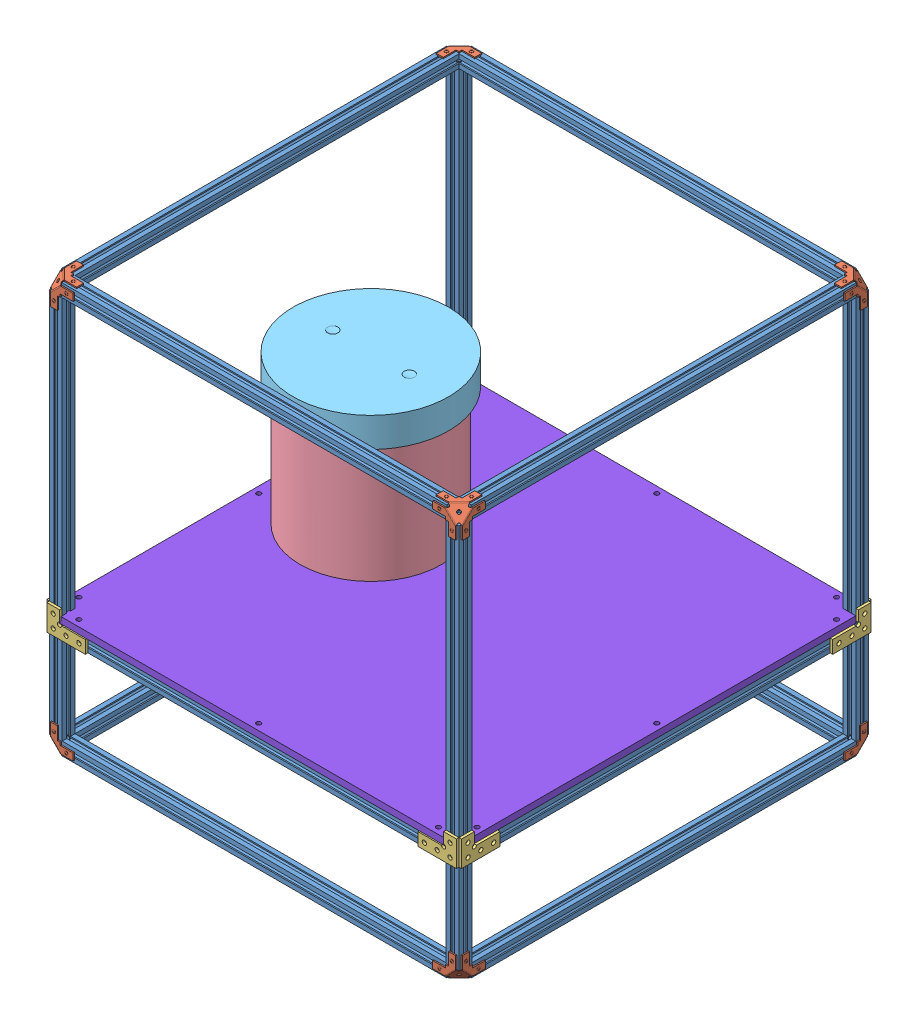
SolidWorks assembly body_assem, configuration Default. Lengths in mm.
Overall size (323 321.3 323).
38 component instances, 8 part files, 96 mates.
Components (placement in the parent):
- 1010extrusion_300-13: 1010extrusion_300 [Default] at (-139.7052 7.1905 -149.8431) size (10 10 300)
- 1959N550_MINIATURE T-SLOTTED FRAMING-9: 1959N550_MINIATURE T-SLOTTED FRAMING [1959N55] at (-145.2052 6.6905 155.1569) x (0 0 1) z (-1 0 0) size (20.65 20.65 20.65)
- 1010extrusion_300-14: 1010extrusion_300 [Default] at (164.7948 7.1905 154.6569) x (0 0 1) z (-1 0 0) size (10 10 300)
- 1010extrusion_300-15: 1010extrusion_300 [Default] at (-139.7052 311.6905 154.6569) x (1 0 0) z (0 -1 0) size (10 10 300)
- 1959N550_MINIATURE T-SLOTTED FRAMING-10: 1959N550_MINIATURE T-SLOTTED FRAMING [1959N55] at (-140.2052 6.6905 -159.8431) x (-1 0 0) z (0 0 -1) size (20.65 20.65 20.65)
- 1010extrusion_300-16: 1010extrusion_300 [Default] at (-139.7052 311.6905 -154.3431) x (1 0 0) z (0 -1 0) size (10 10 300)
- 1010extrusion_300-17: 1010extrusion_300 [Default] at (164.7948 7.1905 -154.3431) x (0 0 1) z (-1 0 0) size (10 10 300)
- 1959N550_MINIATURE T-SLOTTED FRAMING-11: 1959N550_MINIATURE T-SLOTTED FRAMING [1959N55] at (169.7948 6.6905 160.1569) size (20.65 20.65 20.65)
- 1959N550_MINIATURE T-SLOTTED FRAMING-12: 1959N550_MINIATURE T-SLOTTED FRAMING [1959N55] at (174.7948 6.6905 -154.8431) x (0 0 -1) z (1 0 0) size (20.65 20.65 20.65)
- 1010extrusion_300-18: 1010extrusion_300 [Default] at (169.2948 311.6905 154.6569) x (1 0 0) z (0 -1 0) size (10 10 300)
- 1010extrusion_300-19: 1010extrusion_300 [Default] at (169.2948 7.1905 -149.8431) size (10 10 300)
- 1010extrusion_300-20: 1010extrusion_300 [Default] at (169.2948 311.6905 -154.3431) x (1 0 0) z (0 -1 0) size (10 10 300)
- 1010extrusion_300-21: 1010extrusion_300 [Default] at (169.2948 316.1905 150.1569) x (1 0 0) z (0 0 -1) size (10 10 300)
- 1010extrusion_300-22: 1010extrusion_300 [Default] at (164.7948 316.1905 -154.3431) x (0 0 -1) z (-1 0 0) size (10 10 300)
- 1959N550_MINIATURE T-SLOTTED FRAMING-13: 1959N550_MINIATURE T-SLOTTED FRAMING [1959N55] at (169.7948 316.6905 -159.8431) x (1 0 0) z (0 0 -1) size (20.65 20.65 20.65)
- 1959N550_MINIATURE T-SLOTTED FRAMING-14: 1959N550_MINIATURE T-SLOTTED FRAMING [1959N55] at (174.7948 316.6905 155.1569) x (0 0 1) z (1 0 0) size (20.65 20.65 20.65)
- 1010extrusion_300-23: 1010extrusion_300 [Default] at (164.7948 316.1905 154.6569) x (0 0 -1) z (-1 0 0) size (10 10 300)
- 1959N550_MINIATURE T-SLOTTED FRAMING-15: 1959N550_MINIATURE T-SLOTTED FRAMING [1959N55] at (-140.2052 316.6905 160.1569) x (-1 0 0) z (0 0 1) size (20.65 20.65 20.65)
- 1010extrusion_300-24: 1010extrusion_300 [Default] at (-139.7052 316.1905 150.1569) x (1 0 0) z (0 0 -1) size (10 10 300)
- 1959N550_MINIATURE T-SLOTTED FRAMING-16: 1959N550_MINIATURE T-SLOTTED FRAMING [1959N55] at (-145.2052 316.6905 -154.8431) x (0 0 -1) z (-1 0 0) size (20.65 20.65 20.65)
- 1010extrusion_300-25: 1010extrusion_300 [Default] at (169.2948 86.6905 -150.3431) size (10 10 300)
- 1010extrusion_300-26: 1010extrusion_300 [Default] at (165.2948 86.6905 154.6569) x (0 0 1) z (-1 0 0) size (10 10 300)
- 1010extrusion_300-27: 1010extrusion_300 [Default] at (164.2948 86.6905 -154.3431) x (0 0 1) z (-1 0 0) size (10 10 300)
- 1010extrusion_300-28: 1010extrusion_300 [Default] at (-139.7052 86.6905 -150.3431) size (10 10 300)
- 1959N430_MINIATURE T-SLOTTED FRAMING-1: 1959N430_MINIATURE T-SLOTTED FRAMING [1959N43] at (175.2948 91.6905 144.6569) x (0 1 0) z (-1 0 0) size (20 30 2)
- 1959N430_MINIATURE T-SLOTTED FRAMING-2: 1959N430_MINIATURE T-SLOTTED FRAMING [1959N43] at (-129.7052 91.6905 -160.3431) x (0 1 0) z (0 0 -1) size (20 30 2)
- 1959N430_MINIATURE T-SLOTTED FRAMING-3: 1959N430_MINIATURE T-SLOTTED FRAMING [1959N43] at (175.2948 91.6905 -144.3431) x (0 1 0) z (1 0 0) size (20 30 2)
- 1959N430_MINIATURE T-SLOTTED FRAMING-4: 1959N430_MINIATURE T-SLOTTED FRAMING [1959N43] at (159.2948 91.6905 -160.3431) x (0 1 0) z (0 0 1) size (20 30 2)
- 1959N430_MINIATURE T-SLOTTED FRAMING-5: 1959N430_MINIATURE T-SLOTTED FRAMING [1959N43] at (-145.7052 91.6905 -144.3431) x (0 1 0) z (1 0 0) size (20 30 2)
- 1959N430_MINIATURE T-SLOTTED FRAMING-6: 1959N430_MINIATURE T-SLOTTED FRAMING [1959N43] at (-129.7052 91.6905 160.6569) x (0 1 0) z (0 0 -1) size (20 30 2)
- 1959N430_MINIATURE T-SLOTTED FRAMING-7: 1959N430_MINIATURE T-SLOTTED FRAMING [1959N43] at (-145.7052 91.6905 144.6569) x (0 1 0) z (-1 0 0) size (20 30 2)
- 1959N430_MINIATURE T-SLOTTED FRAMING-8: 1959N430_MINIATURE T-SLOTTED FRAMING [1959N43] at (159.2948 91.6905 160.6569) x (0 1 0) z (0 0 1) size (20 30 2)
- tank_assem-1: tank_assem [Default] at (-52.8309 129.2242 1.1692) size (121 127.9 121)
  - tank_body-1: tank_body [Default] at origin size (110 110.17 112.27)
  - tank_cap-1: tank_cap [Default] at (0 102.0838 0) x (-1 0 0) z (0 0 1) size (121 23 121)
  - tank_body_fitting_mount-1: tank_body_fitting_mount [Default] at (0 -8.8163 0) x (1 0 0) z (0 -1 0) size (22 22 17)
  - brass_fitting_joint_noprint-1: brass_fitting_joint_noprint [Default] at (0 -16.8163 0) x (-0.837169 0 -0.546944) z (0 1 0) size (23.09 20.21 12)
- base_plate-1: base_plate [Default] at (-135.7052 91.6905 -149.3431) x (1 0 0) z (0 1 0) size (320 320 5)
Mates (geometry in assembly coordinates):
- Coincident1: coincident anti-aligned: plane of 1010extrusion_300-13 through (-139.7052 2.1905 150.1569) normal (0 -1 0); plane of 1959N550_MINIATURE T-SLOTTED FRAMING-9 through (-140.2052 2.1905 155.1569) normal (0 1 0)
- Coincident2: coincident anti-aligned: plane of 1010extrusion_300-13 through (-144.7052 7.1905 150.1569) normal (-1 0 0); plane of 1959N550_MINIATURE T-SLOTTED FRAMING-9 through (-144.7052 6.6905 155.1569) normal (1 0 0)
- Coincident3: coincident anti-aligned: plane of 1010extrusion_300-13 through (-139.7052 7.1905 150.1569) normal (0 0 1); plane of 1959N550_MINIATURE T-SLOTTED FRAMING-9 through (-145.7052 9.4405 150.1569) normal (0 0 -1)
- Coincident4: coincident anti-aligned: plane of 1959N550_MINIATURE T-SLOTTED FRAMING-9 through (-140.2052 2.1905 155.1569) normal (0 1 0); plane of 1010extrusion_300-14 through (-135.2052 2.1905 154.6569) normal (0 -1 0)
- Coincident5: coincident anti-aligned: plane of 1959N550_MINIATURE T-SLOTTED FRAMING-9 through (-140.2052 6.6905 159.6569) normal (0 0 -1); plane of 1010extrusion_300-14 through (-135.2052 7.1905 159.6569) normal (0 0 1)
- Coincident6: coincident anti-aligned: plane of 1959N550_MINIATURE T-SLOTTED FRAMING-9 through (-135.2052 9.4405 159.6569) normal (1 0 0); plane of 1010extrusion_300-14 through (-135.2052 7.1905 154.6569) normal (-1 0 0)
- Coincident7: coincident anti-aligned: plane of 1959N550_MINIATURE T-SLOTTED FRAMING-9 through (-140.2052 6.6905 159.6569) normal (0 0 -1); plane of 1010extrusion_300-15 through (-139.7052 11.6905 159.6569) normal (0 0 1)
- Coincident8: coincident anti-aligned: plane of 1959N550_MINIATURE T-SLOTTED FRAMING-9 through (-144.7052 6.6905 155.1569) normal (1 0 0); plane of 1010extrusion_300-15 through (-144.7052 11.6905 154.6569) normal (-1 0 0)
- Coincident9: coincident anti-aligned: plane of 1959N550_MINIATURE T-SLOTTED FRAMING-9 through (-135.2052 11.6905 159.6569) normal (0 1 0); plane of 1010extrusion_300-15 through (-139.7052 11.6905 154.6569) normal (0 -1 0)
- Coincident10: coincident anti-aligned: plane of 1010extrusion_300-13 through (-144.7052 7.1905 150.1569) normal (-1 0 0); plane of 1959N550_MINIATURE T-SLOTTED FRAMING-10 through (-144.7052 6.6905 -154.8431) normal (1 0 0)
- Coincident11: coincident anti-aligned: plane of 1010extrusion_300-13 through (-139.7052 2.1905 150.1569) normal (0 -1 0); plane of 1959N550_MINIATURE T-SLOTTED FRAMING-10 through (-140.2052 2.1905 -154.8431) normal (0 1 0)
- Coincident12: coincident anti-aligned: plane of 1010extrusion_300-13 through (-139.7052 7.1905 -149.8431) normal (0 0 -1); plane of 1959N550_MINIATURE T-SLOTTED FRAMING-10 through (-135.2052 2.1905 -149.8431) normal (0 0 1)
- Coincident13: coincident anti-aligned: plane of 1959N550_MINIATURE T-SLOTTED FRAMING-10 through (-140.2052 6.6905 -159.3431) normal (0 0 1); plane of 1010extrusion_300-16 through (-139.7052 11.6905 -159.3431) normal (0 0 -1)
- Coincident14: coincident anti-aligned: plane of 1959N550_MINIATURE T-SLOTTED FRAMING-10 through (-144.7052 6.6905 -154.8431) normal (1 0 0); plane of 1010extrusion_300-16 through (-144.7052 11.6905 -154.3431) normal (-1 0 0)
- Coincident15: coincident anti-aligned: plane of 1959N550_MINIATURE T-SLOTTED FRAMING-10 through (-135.2052 11.6905 -160.3431) normal (0 1 0); plane of 1010extrusion_300-16 through (-139.7052 11.6905 -154.3431) normal (0 -1 0)
- Coincident16: coincident anti-aligned: plane of 1959N550_MINIATURE T-SLOTTED FRAMING-10 through (-140.2052 6.6905 -159.3431) normal (0 0 1); plane of 1010extrusion_300-17 through (-135.2052 7.1905 -159.3431) normal (0 0 -1)
- Coincident17: coincident anti-aligned: plane of 1959N550_MINIATURE T-SLOTTED FRAMING-10 through (-140.2052 2.1905 -154.8431) normal (0 1 0); plane of 1010extrusion_300-17 through (-135.2052 2.1905 -154.3431) normal (0 -1 0)
- Coincident18: coincident anti-aligned: plane of 1959N550_MINIATURE T-SLOTTED FRAMING-10 through (-135.2052 9.4405 -160.3431) normal (1 0 0); plane of 1010extrusion_300-17 through (-135.2052 7.1905 -154.3431) normal (-1 0 0)
- Coincident19: coincident anti-aligned: plane of 1010extrusion_300-14 through (-135.2052 2.1905 154.6569) normal (0 -1 0); plane of 1959N550_MINIATURE T-SLOTTED FRAMING-11 through (169.7948 2.1905 155.1569) normal (0 1 0)
- Coincident20: coincident anti-aligned: plane of 1010extrusion_300-14 through (-135.2052 7.1905 159.6569) normal (0 0 1); plane of 1959N550_MINIATURE T-SLOTTED FRAMING-11 through (169.7948 6.6905 159.6569) normal (0 0 -1)
- Coincident21: coincident anti-aligned: plane of 1010extrusion_300-14 through (164.7948 7.1905 154.6569) normal (1 0 0); plane of 1959N550_MINIATURE T-SLOTTED FRAMING-11 through (164.7948 9.4405 160.6569) normal (-1 0 0)
- Coincident22: coincident anti-aligned: plane of 1959N550_MINIATURE T-SLOTTED FRAMING-11 through (169.7948 6.6905 159.6569) normal (0 0 -1); plane of 1010extrusion_300-18 through (169.2948 11.6905 159.6569) normal (0 0 1)
- Coincident23: coincident anti-aligned: plane of 1959N550_MINIATURE T-SLOTTED FRAMING-11 through (174.2948 6.6905 155.1569) normal (-1 0 0); plane of 1010extrusion_300-18 through (174.2948 11.6905 154.6569) normal (1 0 0)
- Coincident24: coincident anti-aligned: plane of 1959N550_MINIATURE T-SLOTTED FRAMING-11 through (174.2948 11.6905 150.1569) normal (0 1 0); plane of 1010extrusion_300-18 through (169.2948 11.6905 154.6569) normal (0 -1 0)
- Coincident25: coincident anti-aligned: plane of 1959N550_MINIATURE T-SLOTTED FRAMING-11 through (169.7948 2.1905 155.1569) normal (0 1 0); plane of 1010extrusion_300-19 through (169.2948 2.1905 150.1569) normal (0 -1 0)
- Coincident26: coincident anti-aligned: plane of 1959N550_MINIATURE T-SLOTTED FRAMING-11 through (174.2948 6.6905 155.1569) normal (-1 0 0); plane of 1010extrusion_300-19 through (174.2948 7.1905 150.1569) normal (1 0 0)
- Coincident27: coincident anti-aligned: plane of 1959N550_MINIATURE T-SLOTTED FRAMING-11 through (174.2948 9.4405 150.1569) normal (0 0 -1); plane of 1010extrusion_300-19 through (169.2948 7.1905 150.1569) normal (0 0 1)
- Coincident28: coincident anti-aligned: plane of 1959N550_MINIATURE T-SLOTTED FRAMING-12 through (169.7948 2.1905 -154.8431) normal (0 1 0); plane of 1010extrusion_300-19 through (169.2948 2.1905 150.1569) normal (0 -1 0)
- Coincident29: coincident anti-aligned: plane of 1959N550_MINIATURE T-SLOTTED FRAMING-12 through (174.2948 6.6905 -154.8431) normal (-1 0 0); plane of 1010extrusion_300-19 through (174.2948 7.1905 150.1569) normal (1 0 0)
- Coincident30: coincident anti-aligned: plane of 1959N550_MINIATURE T-SLOTTED FRAMING-12 through (175.2948 9.4405 -149.8431) normal (0 0 1); plane of 1010extrusion_300-19 through (169.2948 7.1905 -149.8431) normal (0 0 -1)
- Coincident31: coincident anti-aligned: plane of 1959N550_MINIATURE T-SLOTTED FRAMING-12 through (169.7948 6.6905 -159.3431) normal (0 0 1); plane of 1010extrusion_300-20 through (169.2948 11.6905 -159.3431) normal (0 0 -1)
- Coincident32: coincident anti-aligned: plane of 1959N550_MINIATURE T-SLOTTED FRAMING-12 through (174.2948 6.6905 -154.8431) normal (-1 0 0); plane of 1010extrusion_300-20 through (174.2948 11.6905 -154.3431) normal (1 0 0)
- Coincident33: coincident anti-aligned: plane of 1959N550_MINIATURE T-SLOTTED FRAMING-12 through (164.7948 11.6905 -159.3431) normal (0 1 0); plane of 1010extrusion_300-20 through (169.2948 11.6905 -154.3431) normal (0 -1 0)
- Coincident34: coincident anti-aligned: plane of 1959N550_MINIATURE T-SLOTTED FRAMING-15 through (-135.2052 321.1905 150.1569) normal (0 0 -1); plane of 1010extrusion_300-24 through (-139.7052 316.1905 150.1569) normal (0 0 1)
- Coincident35: coincident anti-aligned: plane of 1959N550_MINIATURE T-SLOTTED FRAMING-15 through (-140.2052 321.1905 155.1569) normal (0 -1 0); plane of 1010extrusion_300-24 through (-139.7052 321.1905 -149.8431) normal (0 1 0)
- Coincident36: coincident anti-aligned: plane of 1959N550_MINIATURE T-SLOTTED FRAMING-15 through (-144.7052 316.6905 155.1569) normal (1 0 0); plane of 1010extrusion_300-24 through (-144.7052 316.1905 -149.8431) normal (-1 0 0)
- Coincident37: coincident anti-aligned: plane of 1010extrusion_300-23 through (-135.2052 316.1905 154.6569) normal (-1 0 0); plane of 1959N550_MINIATURE T-SLOTTED FRAMING-15 through (-135.2052 313.9405 160.6569) normal (1 0 0)
- Coincident38: coincident anti-aligned: plane of 1010extrusion_300-23 through (-135.2052 316.1905 159.6569) normal (0 0 1); plane of 1959N550_MINIATURE T-SLOTTED FRAMING-15 through (-140.2052 316.6905 159.6569) normal (0 0 -1)
- Coincident39: coincident anti-aligned: plane of 1010extrusion_300-23 through (-135.2052 321.1905 154.6569) normal (0 1 0); plane of 1959N550_MINIATURE T-SLOTTED FRAMING-15 through (-140.2052 321.1905 155.1569) normal (0 -1 0)
- Coincident40: coincident anti-aligned: plane of 1010extrusion_300-21 through (169.2948 316.1905 150.1569) normal (0 0 1); plane of 1959N550_MINIATURE T-SLOTTED FRAMING-14 through (175.2948 313.9405 150.1569) normal (0 0 -1)
- Coincident41: coincident anti-aligned: plane of 1010extrusion_300-24 through (-139.7052 321.1905 -149.8431) normal (0 1 0); plane of 1959N550_MINIATURE T-SLOTTED FRAMING-16 through (-140.2052 321.1905 -154.8431) normal (0 -1 0)
- Coincident42: coincident anti-aligned: plane of 1010extrusion_300-24 through (-144.7052 316.1905 -149.8431) normal (-1 0 0); plane of 1959N550_MINIATURE T-SLOTTED FRAMING-16 through (-144.7052 316.6905 -154.8431) normal (1 0 0)
- Coincident43: coincident anti-aligned: plane of 1010extrusion_300-24 through (-139.7052 316.1905 -149.8431) normal (0 0 -1); plane of 1959N550_MINIATURE T-SLOTTED FRAMING-16 through (-145.7052 313.9405 -149.8431) normal (0 0 1)
- Coincident44: coincident anti-aligned: plane of 1010extrusion_300-22 through (-135.2052 316.1905 -159.3431) normal (0 0 -1); plane of 1959N550_MINIATURE T-SLOTTED FRAMING-16 through (-140.2052 316.6905 -159.3431) normal (0 0 1)
- Coincident45: coincident anti-aligned: plane of 1010extrusion_300-22 through (164.7948 316.1905 -154.3431) normal (1 0 0); plane of 1959N550_MINIATURE T-SLOTTED FRAMING-13 through (164.7948 313.9405 -160.3431) normal (-1 0 0)
- Coincident46: coincident anti-aligned: plane of 1010extrusion_300-21 through (169.2948 316.1905 -149.8431) normal (0 0 -1); plane of 1959N550_MINIATURE T-SLOTTED FRAMING-13 through (174.2948 313.9405 -149.8431) normal (0 0 1)
- Coincident47: coincident anti-aligned: plane of 1010extrusion_300-21 through (169.2948 321.1905 -149.8431) normal (0 1 0); plane of 1959N550_MINIATURE T-SLOTTED FRAMING-13 through (169.7948 321.1905 -154.8431) normal (0 -1 0)
- Coincident48: coincident anti-aligned: plane of 1010extrusion_300-21 through (174.2948 316.1905 -149.8431) normal (1 0 0); plane of 1959N550_MINIATURE T-SLOTTED FRAMING-13 through (174.2948 316.6905 -154.8431) normal (-1 0 0)
- Coincident49: coincident anti-aligned: plane of 1010extrusion_300-21 through (174.2948 316.1905 -149.8431) normal (1 0 0); plane of 1959N550_MINIATURE T-SLOTTED FRAMING-14 through (174.2948 316.6905 155.1569) normal (-1 0 0)
- Coincident50: coincident anti-aligned: plane of 1010extrusion_300-21 through (169.2948 321.1905 -149.8431) normal (0 1 0); plane of 1959N550_MINIATURE T-SLOTTED FRAMING-14 through (169.7948 321.1905 155.1569) normal (0 -1 0)
- Coincident51: coincident anti-aligned: plane of 1010extrusion_300-22 through (-135.2052 321.1905 -154.3431) normal (0 1 0); plane of 1959N550_MINIATURE T-SLOTTED FRAMING-16 through (-140.2052 321.1905 -154.8431) normal (0 -1 0)
- Coincident52: coincident anti-aligned: plane of 1010extrusion_300-22 through (-135.2052 321.1905 -154.3431) normal (0 1 0); plane of 1959N550_MINIATURE T-SLOTTED FRAMING-13 through (169.7948 321.1905 -154.8431) normal (0 -1 0)
- Coincident53: coincident anti-aligned: plane of 1010extrusion_300-22 through (-135.2052 316.1905 -159.3431) normal (0 0 -1); plane of 1959N550_MINIATURE T-SLOTTED FRAMING-13 through (169.7948 316.6905 -159.3431) normal (0 0 1)
- Coincident54: coincident anti-aligned: plane of 1010extrusion_300-22 through (-135.2052 316.1905 -154.3431) normal (-1 0 0); plane of 1959N550_MINIATURE T-SLOTTED FRAMING-16 through (-135.2052 313.9405 -159.3431) normal (1 0 0)
- Coincident56: coincident anti-aligned: plane of 1010extrusion_300-18 through (174.2948 11.6905 154.6569) normal (1 0 0); plane of 1959N550_MINIATURE T-SLOTTED FRAMING-14 through (174.2948 316.6905 155.1569) normal (-1 0 0)
- Coincident57: coincident anti-aligned: plane of 1010extrusion_300-18 through (169.2948 11.6905 159.6569) normal (0 0 1); plane of 1959N550_MINIATURE T-SLOTTED FRAMING-14 through (169.7948 316.6905 159.6569) normal (0 0 -1)
- Coincident58: coincident anti-aligned: plane of 1010extrusion_300-18 through (169.2948 311.6905 154.6569) normal (0 1 0); plane of 1959N550_MINIATURE T-SLOTTED FRAMING-14 through (175.2948 311.6905 150.1569) normal (0 -1 0)
- Coincident59: coincident anti-aligned: plane of 1010extrusion_300-15 through (-134.7052 11.6905 154.6569) normal (1 0 0); plane of 1010extrusion_300-26 through (-134.7052 86.6905 154.6569) normal (-1 0 0)
- Coincident60: coincident aligned: plane of 1010extrusion_300-15 through (-139.7052 11.6905 159.6569) normal (0 0 1); plane of 1010extrusion_300-26 through (-134.7052 86.6905 159.6569) normal (0 0 1)
- Coincident61: coincident anti-aligned: plane of 1010extrusion_300-15 through (-139.7052 11.6905 149.6569) normal (0 0 -1); plane of 1010extrusion_300-28 through (-139.7052 86.6905 149.6569) normal (0 0 1)
- Coincident63: coincident aligned: plane of 1010extrusion_300-15 through (-144.7052 11.6905 154.6569) normal (-1 0 0); plane of 1010extrusion_300-28 through (-144.7052 86.6905 149.6569) normal (-1 0 0)
- Coincident64: coincident anti-aligned: plane of 1010extrusion_300-18 through (169.2948 11.6905 149.6569) normal (0 0 -1); plane of 1010extrusion_300-25 through (169.2948 86.6905 149.6569) normal (0 0 1)
- Coincident65: coincident aligned: plane of 1010extrusion_300-18 through (174.2948 11.6905 154.6569) normal (1 0 0); plane of 1010extrusion_300-25 through (174.2948 86.6905 149.6569) normal (1 0 0)
- Coincident66: coincident aligned: plane of 1010extrusion_300-20 through (169.2948 11.6905 -159.3431) normal (0 0 -1); plane of 1010extrusion_300-27 through (-135.7052 86.6905 -159.3431) normal (0 0 -1)
- Coincident67: coincident anti-aligned: plane of 1010extrusion_300-20 through (164.2948 11.6905 -154.3431) normal (-1 0 0); plane of 1010extrusion_300-27 through (164.2948 86.6905 -154.3431) normal (1 0 0)
- Coincident72: coincident anti-aligned: plane of 1010extrusion_300-26 through (-134.7052 91.6905 154.6569) normal (0 1 0)
- Coincident73: coincident anti-aligned: plane of 1010extrusion_300-28 through (-139.7052 91.6905 149.6569) normal (0 1 0)
- Coincident74: coincident anti-aligned: plane of 1010extrusion_300-25 through (169.2948 91.6905 149.6569) normal (0 1 0)
- Coincident75: coincident anti-aligned: plane of 1010extrusion_300-27 through (-135.7052 91.6905 -154.3431) normal (0 1 0)
- Coincident76: coincident anti-aligned: plane of 1010extrusion_300-18 through (174.2948 11.6905 154.6569) normal (1 0 0); plane of 1959N430_MINIATURE T-SLOTTED FRAMING-1 through (174.2948 91.6905 149.6569) normal (-1 0 0)
- Coincident77: coincident aligned: plane of 1010extrusion_300-18 through (169.2948 11.6905 159.6569) normal (0 0 1); plane of 1959N430_MINIATURE T-SLOTTED FRAMING-1 through (174.2948 81.6905 159.6569) normal (0 0 1)
- Coincident78: coincident aligned: plane of 1010extrusion_300-25 through (169.2948 81.6905 149.6569) normal (0 -1 0); plane of 1959N430_MINIATURE T-SLOTTED FRAMING-1 through (174.2948 81.6905 129.6569) normal (0 -1 0)
- Coincident90: coincident anti-aligned: plane of 1010extrusion_300-25 through (174.2948 86.6905 149.6569) normal (1 0 0); plane of 1959N430_MINIATURE T-SLOTTED FRAMING-3 through (174.2948 91.6905 -149.3431) normal (-1 0 0)
- Coincident91: coincident aligned: plane of 1010extrusion_300-25 through (169.2948 91.6905 149.6569) normal (0 1 0); plane of 1959N430_MINIATURE T-SLOTTED FRAMING-3 through (176.2948 91.6905 -129.3431) normal (0 1 0)
- Coincident92: coincident aligned: plane of 1010extrusion_300-20 through (169.2948 11.6905 -149.3431) normal (0 0 1); plane of 1959N430_MINIATURE T-SLOTTED FRAMING-3 through (176.2948 93.3405 -149.3431) normal (0 0 1)
- Coincident93: coincident anti-aligned: plane of 1010extrusion_300-16 through (-139.7052 11.6905 -159.3431) normal (0 0 -1); plane of 1959N430_MINIATURE T-SLOTTED FRAMING-2 through (-134.7052 91.6905 -159.3431) normal (0 0 1)
- Coincident94: coincident aligned: plane of 1010extrusion_300-27 through (-135.7052 91.6905 -154.3431) normal (0 1 0); plane of 1959N430_MINIATURE T-SLOTTED FRAMING-2 through (-114.7052 91.6905 -161.3431) normal (0 1 0)
- Coincident95: coincident aligned: plane of 1010extrusion_300-16 through (-134.7052 11.6905 -154.3431) normal (1 0 0); plane of 1959N430_MINIATURE T-SLOTTED FRAMING-2 through (-134.7052 93.3405 -161.3431) normal (1 0 0)
- Coincident96: coincident anti-aligned: plane of 1010extrusion_300-20 through (169.2948 11.6905 -159.3431) normal (0 0 -1); plane of 1959N430_MINIATURE T-SLOTTED FRAMING-4 through (164.2948 91.6905 -159.3431) normal (0 0 1)
- Coincident98: coincident aligned: plane of 1010extrusion_300-20 through (164.2948 11.6905 -154.3431) normal (-1 0 0); plane of 1959N430_MINIATURE T-SLOTTED FRAMING-4 through (164.2948 93.3405 -159.3431) normal (-1 0 0)
- Coincident99: coincident aligned: plane of 1010extrusion_300-27 through (-135.7052 91.6905 -154.3431) normal (0 1 0); plane of 1959N430_MINIATURE T-SLOTTED FRAMING-4 through (144.2948 91.6905 -159.3431) normal (0 1 0)
- Coincident100: coincident anti-aligned: plane of 1010extrusion_300-28 through (-144.7052 86.6905 149.6569) normal (-1 0 0); plane of 1959N430_MINIATURE T-SLOTTED FRAMING-5 through (-144.7052 91.6905 -149.3431) normal (1 0 0)
- Coincident101: coincident aligned: plane of 1010extrusion_300-16 through (-139.7052 11.6905 -149.3431) normal (0 0 1); plane of 1959N430_MINIATURE T-SLOTTED FRAMING-5 through (-144.7052 93.3405 -149.3431) normal (0 0 1)
- Coincident102: coincident aligned: plane of 1010extrusion_300-28 through (-139.7052 91.6905 149.6569) normal (0 1 0); plane of 1959N430_MINIATURE T-SLOTTED FRAMING-5 through (-144.7052 91.6905 -129.3431) normal (0 1 0)
- Coincident103: coincident anti-aligned: plane of 1010extrusion_300-26 through (-134.7052 86.6905 159.6569) normal (0 0 1); plane of 1959N430_MINIATURE T-SLOTTED FRAMING-6 through (-134.7052 91.6905 159.6569) normal (0 0 -1)
- Coincident104: coincident aligned: plane of 1010extrusion_300-26 through (-134.7052 91.6905 154.6569) normal (0 1 0); plane of 1959N430_MINIATURE T-SLOTTED FRAMING-6 through (-114.7052 91.6905 159.6569) normal (0 1 0)
- Coincident105: coincident aligned: plane of 1010extrusion_300-15 through (-144.7052 11.6905 154.6569) normal (-1 0 0); plane of 1959N430_MINIATURE T-SLOTTED FRAMING-6 through (-144.7052 81.6905 159.6569) normal (-1 0 0)
- Coincident106: coincident anti-aligned: plane of 1010extrusion_300-15 through (-144.7052 11.6905 154.6569) normal (-1 0 0); plane of 1959N430_MINIATURE T-SLOTTED FRAMING-7 through (-144.7052 91.6905 149.6569) normal (1 0 0)
- Coincident107: coincident aligned: plane of 1010extrusion_300-15 through (-139.7052 11.6905 159.6569) normal (0 0 1); plane of 1959N430_MINIATURE T-SLOTTED FRAMING-7 through (-146.7052 81.6905 159.6569) normal (0 0 1)
- Coincident109: coincident aligned: plane of 1010extrusion_300-28 through (-139.7052 91.6905 149.6569) normal (0 1 0); plane of 1959N430_MINIATURE T-SLOTTED FRAMING-7 through (-146.7052 91.6905 129.6569) normal (0 1 0)
- Coincident110: coincident anti-aligned: plane of 1010extrusion_300-26 through (-134.7052 86.6905 159.6569) normal (0 0 1); plane of 1959N430_MINIATURE T-SLOTTED FRAMING-8 through (164.2948 91.6905 159.6569) normal (0 0 -1)
- Coincident111: coincident aligned: plane of 1010extrusion_300-18 through (174.2948 11.6905 154.6569) normal (1 0 0); plane of 1959N430_MINIATURE T-SLOTTED FRAMING-8 through (174.2948 81.6905 161.6569) normal (1 0 0)
- Coincident112: coincident aligned: plane of 1010extrusion_300-26 through (-134.7052 91.6905 154.6569) normal (0 1 0); plane of 1959N430_MINIATURE T-SLOTTED FRAMING-8 through (144.2948 91.6905 161.6569) normal (0 1 0)
- Coincident113: coincident anti-aligned: plane of 1010extrusion_300-28 through (-139.7052 91.6905 149.6569) normal (0 1 0); plane of base_plate-1 through (-135.7052 91.6905 -149.3431) normal (0 -1 0)
- Coincident114: coincident anti-aligned: plane of 1010extrusion_300-20 through (169.2948 11.6905 -149.3431) normal (0 0 1); plane of base_plate-1 through (164.2948 96.6905 -149.3431) normal (0 0 -1)
- Coincident115: coincident aligned: plane of 1010extrusion_300-25 through (174.2948 86.6905 149.6569) normal (1 0 0); plane of base_plate-1 through (174.2948 96.6905 -149.3431) normal (1 0 0)
